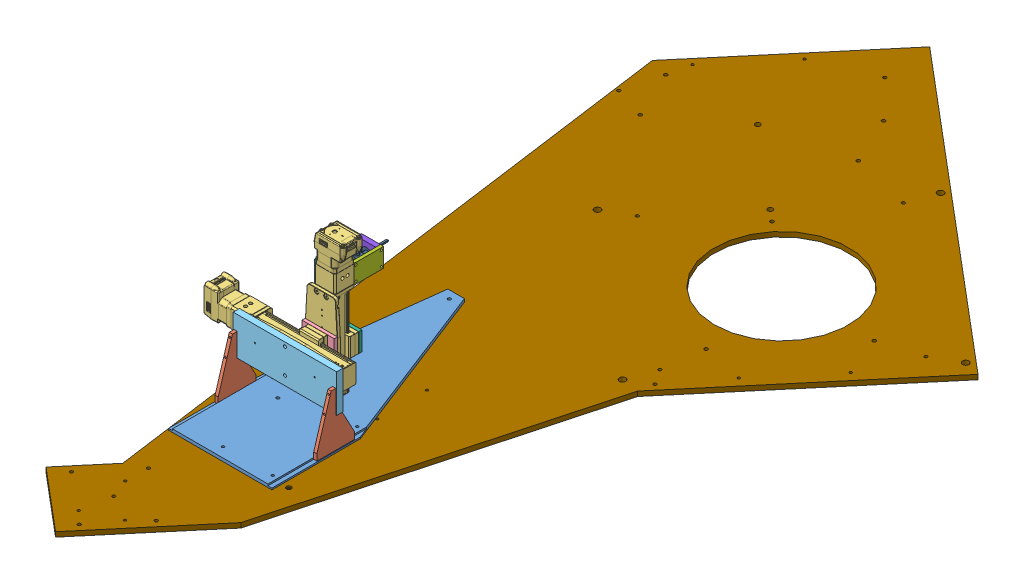
SolidWorks assembly Full Assembly, configuration Default. Lengths in mm.
Overall size (1693.71 300.3 1724.37).
17 component instances, 12 part files, 47 mates.
Components (placement in the parent):
- BasePlate-1: BasePlate [Default] at origin size (207.96 6.35 520.7)
- SideSupport-1: SideSupport [Default] at (7.9375 3.175 -168.275) x (0 0 1) z (0 -1 0) size (76.2 6.35 107.95)
- SideSupport-2: SideSupport [Default] at (206.375 3.175 -168.275) x (0 0 1) z (0 -1 0) size (76.2 6.35 107.95)
- MSL-100-X-3-1: MSL-100-X-3 [Default] at (104.0983 107.6325 -142.875) x (0 -1 0) z (1 0 0) size (69.35 52.11 275.72)
- MSL-100-X-3-2: MSL-100-X-3 [Default] at (111.0271 107.6325 -196.261) x (-1 0 0) z (0 -1 0) size (69.35 52.11 275.72)
- XY Plate-1: XY Plate [Default] at (143.4121 79.0575 -196.261) x (0 1 0) z (1 0 0) size (57.15 6.35 64.77)
- TravelSupport2-1: TravelSupport2 [Default] at (0 64.4525 -142.875) x (0 0 1) z (-1 0 0) size (12.7 76.2 207.96)
- Top Plate2-1: Top Plate2 [Default] at (139.6021 119.7537 -249.647) x (-1 0 0) z (0 1 0) size (88.9 6.35 120.65)
- AngledMount-1: AngledMount [Default] at (79.2771 202.3037 -264.647) x (0 -1 0) z (0 0 1) size (63.5 6.35 82.55)
- CircleMount-1: CircleMount [Default] at (41.1771 189.6037 -337.672) x (0 0 -1) z (-1 0 0) size (9.53 38.1 38.1)
- CircleMount-2: CircleMount [Default] at (41.1771 189.6037 -286.872) x (0 0 -1) z (-1 0 0) size (9.53 38.1 38.1)
- wSMA_M456 Plate-1: wSMA_M456 Plate [Default] at (365.9033 -9.53 -867.6075) x (-0.644556 0 0.764557) z (-0.764557 0 -0.644556) size (1340.6 9.53 1085.1)
- Source-1: Source [Default] at (58.4491 171.9507 -381.0552) x (1 0 0) z (0 -1 0) size (25.4 121.87 45.73)
- Spacer-1: Spacer [Default] at (82.4521 195.9537 -264.647) x (0 0 1) z (-1 0 0) size (15 8 9.24)
- Spacer-2: Spacer [Default] at (82.4521 145.1537 -249.647) x (0 0 -1) z (1 0 0) size (15 8 9.24)
- socket head cap screw_am-2: socket head cap screw_am [B18.3.1M - 4 x 0.7 x 20 Hex SHCS -- 20NHX] at (82.4521 195.9537 -274.997) x (0 0 1) z (-1 0 0) size (24 7 7)
- socket head cap screw_am-3: socket head cap screw_am [B18.3.1M - 4 x 0.7 x 20 Hex SHCS -- 20NHX] at (82.4521 145.1537 -274.997) x (0 0 1) z (-1 0 0) size (24 7 7)
Mates (geometry in assembly coordinates):
- Coincident1: coordinate: point of BasePlate-1; point of assembly
- Coincident2: coincident: plane of BasePlate-1 through (200.025 3.175 -520.7) normal (0 1 0); plane of SideSupport-2 through (200.025 3.175 -168.275) normal (0 -1 0)
- Coincident4: coincident: plane of BasePlate-1 through (200.025 6.35 -520.7) normal (1 0 0); plane of SideSupport-2 through (200.025 3.175 -168.275) normal (-1 0 0)
- Coincident5: coincident: plane of BasePlate-1 through (0 3.175 -520.7) normal (0 1 0); plane of SideSupport-1 through (1.5875 3.175 -168.275) normal (0 -1 0)
- Coincident6: coincident: plane of BasePlate-1 through (7.9375 3.175 -520.7) normal (-1 0 0); plane of SideSupport-1 through (7.9375 3.175 -168.275) normal (1 0 0)
- Coincident7: coincident: plane of SideSupport-1 through (1.5875 15.875 -92.075) normal (0 0 1); plane of SideSupport-2 through (200.025 15.875 -92.075) normal (0 0 1)
- Coincident9: coincident: plane of MSL-100-X-3-1 through (130.0771 79.0575 -189.911) normal (0 0 -1); plane of XY Plate-1 through (143.4121 79.0575 -189.911) normal (0 0 1)
- Concentric4: concentric: cylinder of MSL-100-X-3-1 through (99.9146 84.1375 -189.911) axis (0 0 -1) radius 3.175; cylinder of XY Plate-1 through (99.9146 84.1375 -189.911) axis (0 0 -1) radius 1.5
- Coincident10: coincident: plane of MSL-100-X-3-2 through (139.6021 15.0495 -196.261) normal (0 0 1); plane of XY Plate-1 through (143.4121 79.0575 -196.261) normal (0 0 -1)
- Concentric7: concentric: cylinder of MSL-100-X-3-1 through (99.9146 131.1275 -189.911) axis (0 0 -1) radius 3.175; cylinder of XY Plate-1 through (99.9146 131.1275 -189.911) axis (0 0 -1) radius 1.5
- Concentric8: concentric: cylinder of MSL-100-X-3-2 through (136.0271 107.6325 -196.261) axis (0 0 -1) radius 3.3655; cylinder of XY Plate-1 through (136.0271 107.6325 -189.911) axis (0 0 -1) radius 3
- Concentric9: concentric: cylinder of MSL-100-X-3-2 through (86.0271 107.6325 -196.261) axis (0 0 -1) radius 3.3655; cylinder of XY Plate-1 through (86.0271 107.6325 -189.911) axis (0 0 -1) radius 3
- Coincident16: coincident: plane of SideSupport-2 through (200.025 63.5 -130.175) normal (0 0 -1); plane of TravelSupport2-1 through (0 64.4525 -130.175) normal (0 0 1)
- Coincident17: coincident: cylinder of SideSupport-2 through (203.2 104.775 -92.075) axis (0 0 -1) radius 1.5; circle of TravelSupport2-1
- Concentric12: concentric: cylinder of SideSupport-1 through (4.7625 74.6125 -92.075) axis (0 0 -1) radius 1.5; cylinder of TravelSupport2-1 through (4.7625 74.6125 -130.175) axis (0 0 -1) radius 1.5
- Coincident18: coincident: plane of MSL-100-X-3-1 through (196.6813 136.2075 -142.875) normal (0 0 1); plane of TravelSupport2-1 through (0 64.4525 -142.875) normal (0 0 -1)
- Coincident19: coincident: plane of MSL-100-X-3-2 through (82.4521 81.6537 -243.297) normal (0 0 -1); plane of Top Plate2-1 through (139.6021 119.7537 -243.297) normal (0 0 1)
- Concentric18: concentric: cylinder of MSL-100-X-3-2 through (111.0271 100.7037 -243.297) axis (0 0 -1) radius 1.65; cylinder of Top Plate2-1 through (111.0271 100.7037 -243.297) axis (0 0 -1) radius 2
- Concentric19: concentric: cylinder of MSL-100-X-3-2 through (123.5271 88.2037 -243.297) axis (0 0 -1) radius 1.65; cylinder of Top Plate2-1 through (123.5271 88.2037 -243.297) axis (0 0 -1) radius 2
- Coincident21: coincident: plane of AngledMount-1 through (79.2771 202.3037 -264.647) normal (-1 0 0); plane of CircleMount-1 through (79.2771 189.6037 -347.197) normal (1 0 0)
- Coincident22: coincident: plane of AngledMount-1 through (79.2771 202.3037 -264.647) normal (-1 0 0); plane of CircleMount-2 through (79.2771 189.6037 -296.397) normal (1 0 0)
- Concentric27: concentric: cylinder of Top Plate2-1 through (82.4521 195.9537 -243.297) axis (0 0 -1) radius 2; cylinder of AngledMount-1 through (82.4521 195.9537 -347.197) axis (0 0 1) radius 2
- Concentric28: concentric: cylinder of Top Plate2-1 through (82.4521 145.1537 -243.297) axis (0 0 -1) radius 2; cylinder of AngledMount-1 through (82.4521 145.1537 -347.197) axis (0 0 1) radius 2
- Coincident24: coincident: plane of BasePlate-1 through (0 0 0) normal (0 -1 0); plane of wSMA_M456 Plate-1 through (365.9033 0 -867.6075) normal (0 1 0)
- Concentric30: concentric: cylinder of BasePlate-1 through (60.0617 6.35 -504.825) axis (0 -1 0) radius 3; cylinder of wSMA_M456 Plate-1 through (60.0617 0 -504.825) axis (0 1 0) radius 3
- Distance1: distance = 92.075 mm: plane of BasePlate-1 through (207.9625 6.35 0) normal (0 0 1); plane of SideSupport-2 through (200.025 15.875 -92.075) normal (0 0 1)
- Concentric31: concentric: cylinder of MSL-100-X-3-1 through (43.9813 108.9025 -142.875) axis (0 0 1) radius 1.25; cylinder of TravelSupport2-1 through (43.9813 108.9025 -130.175) axis (0 0 -1) radius 1.27
- Concentric32: concentric: cylinder of MSL-100-X-3-1 through (163.9813 108.9025 -142.875) axis (0 0 1) radius 1.25; cylinder of TravelSupport2-1 through (163.9812 108.9025 -130.175) axis (0 0 -1) radius 1.27
- Concentric33: concentric: cylinder of CircleMount-1 through (60.2271 170.5537 -347.197) axis (0 0 1) radius 9.525; cylinder of Source-1 through (60.2271 170.5537 -338.5102) axis (0 0 -1) radius 9.525
- Coincident25: coincident: plane of CircleMount-2 through (41.1771 189.6037 -286.872) normal (0 0 1); plane of Source-1 through (58.4491 171.9507 -286.872) normal (0 0 -1)
- Parallel2: parallel: plane of AngledMount-1 through (79.2771 202.3037 -264.647) normal (-1 0 0); plane of Source-1 through (72.9271 179.0055 -303.763) normal (1 0 0)
- Concentric34: concentric: cylinder of AngledMount-1 through (82.4521 195.9537 -347.197) axis (0 0 1) radius 2; cylinder of Spacer-1 through (82.4521 195.9537 -249.647) axis (0 0 -1) radius 2
- Coincident30: coincident: plane of AngledMount-1 through (85.6271 202.3037 -264.647) normal (0 0 1); plane of Spacer-1 through (82.4521 195.9537 -264.647) normal (0 0 -1)
- Coincident31: coincident: plane of Top Plate2-1 through (139.6021 119.7537 -249.647) normal (0 0 -1); plane of Spacer-1 through (82.4521 195.9537 -249.647) normal (0 0 1)
- Concentric35: concentric: cylinder of Top Plate2-1 through (82.4521 145.1537 -243.297) axis (0 0 -1) radius 2; cylinder of Spacer-2 through (82.4521 145.1537 -264.647) axis (0 0 1) radius 2
- Coincident32: coincident: plane of AngledMount-1 through (85.6271 202.3037 -264.647) normal (0 0 1); plane of Spacer-2 through (82.4521 145.1537 -264.647) normal (0 0 -1)
- Coincident33: coincident: plane of Top Plate2-1 through (139.6021 119.7537 -249.647) normal (0 0 -1); plane of Spacer-2 through (82.4521 145.1537 -249.647) normal (0 0 1)
- Parallel4: parallel: plane of Spacer-1 through (84.7615 199.9537 -249.647) normal (0 1 0); plane of Spacer-2 through (80.1427 149.1537 -264.647) normal (0 1 0)
- Parallel5: parallel: plane of Top Plate2-1 through (139.6021 202.3037 -243.297) normal (0 1 0); plane of Spacer-1 through (84.7615 199.9537 -249.647) normal (0 1 0)
- Concentric36: concentric: cylinder of AngledMount-1 through (82.4521 195.9537 -347.197) axis (0 0 1) radius 2; cylinder of socket head cap screw_am-2 through (82.4521 195.9537 -306.747) axis (0 0 -1) radius 3.5
- Coincident34: coincident: plane of AngledMount-1 through (85.6271 189.6037 -270.997) normal (0 0 -1); plane of socket head cap screw_am-2 through (82.4521 199.4537 -270.997) normal (0 0 1)
- Concentric37: concentric: cylinder of AngledMount-1 through (82.4521 145.1537 -347.197) axis (0 0 1) radius 2; cylinder of socket head cap screw_am-3 through (82.4521 145.1537 -306.747) axis (0 0 -1) radius 3.5
- Coincident35: coincident: plane of AngledMount-1 through (85.6271 138.8037 -270.997) normal (0 0 -1); plane of socket head cap screw_am-3 through (82.4521 148.6537 -270.997) normal (0 0 1)
- Concentric38: concentric: circle of AngledMount-1; circle of CircleMount-2
- Concentric39: concentric: circle of AngledMount-1; circle of CircleMount-2
- Concentric40: concentric: circle of AngledMount-1; circle of CircleMount-1
- Concentric41: concentric: circle of AngledMount-1; circle of CircleMount-1
